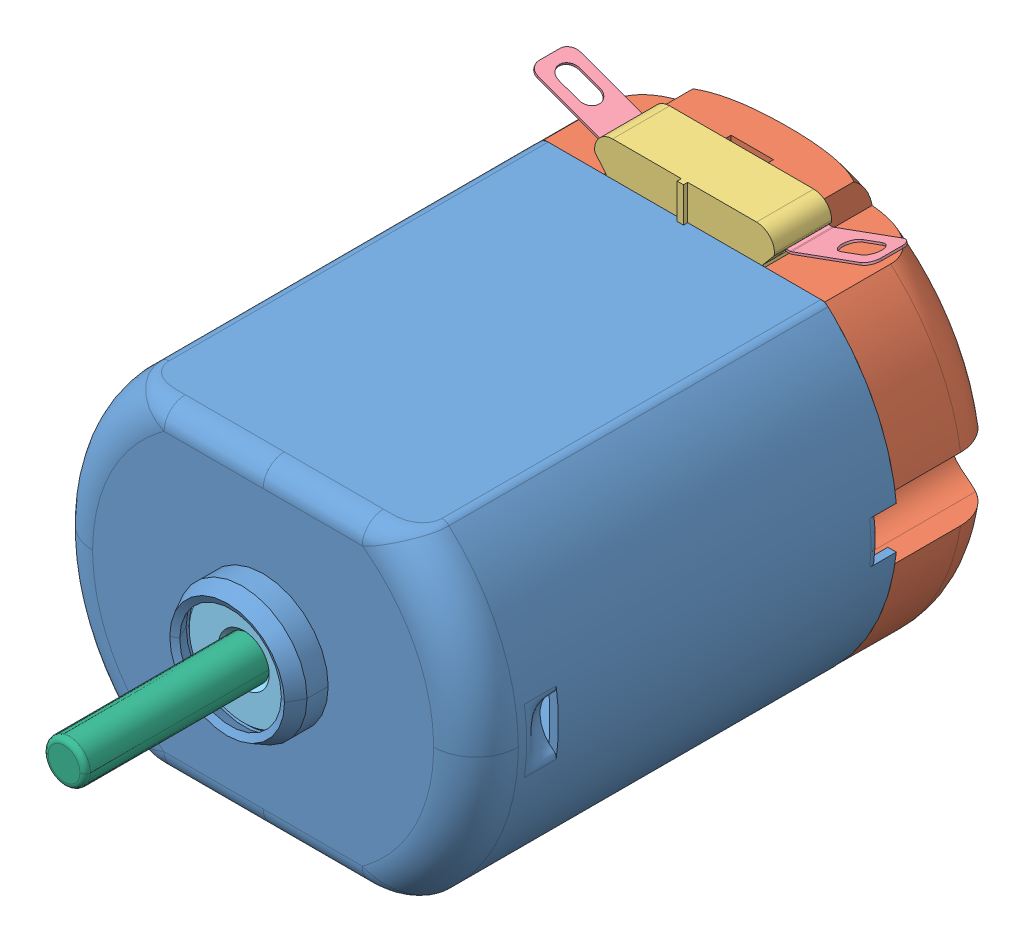
SolidWorks assembly type_fa130, configuration Default. Lengths in mm.
Overall size (20.11 18.59 38).
8 component instances, 6 part files, 0 mates.
Components (placement in the parent):
- type_fa130.STEP-1: type_fa130.STEP [Default] at origin size (20.11 18.59 38)
  - housing.STEP-1: housing.STEP [Default] at origin size (20.11 16.36 21.6)
  - endbell.STEP-1: endbell.STEP [Default] at origin size (19.88 17.28 10.8)
  - brushholder.STEP-1: brushholder.STEP [Default] at (0 9.2 0) x (-1 0 0) z (0 0 -1) size (8.5 5.2 4.2)
  - brush.STEP-1: brush.STEP [Default] at (1.7963 5.1456 -1.7) x (0.984808 -0.173648 0) z (0 0 1) size (5.48 5.35 2)
  - brush.STEP-2: brush.STEP [Default] at (-1.7963 5.1456 -1.7) x (-0.984808 -0.173648 0) z (0 0 -1) size (5.48 5.35 2)
  - bush.STEP-1: bush.STEP [Default] at (0 0 19.0142) size (5.55 5.55 1.8)
  - shaft.STEP-1: shaft.STEP [Default] at (0 0 10.3) size (2 2 38)
